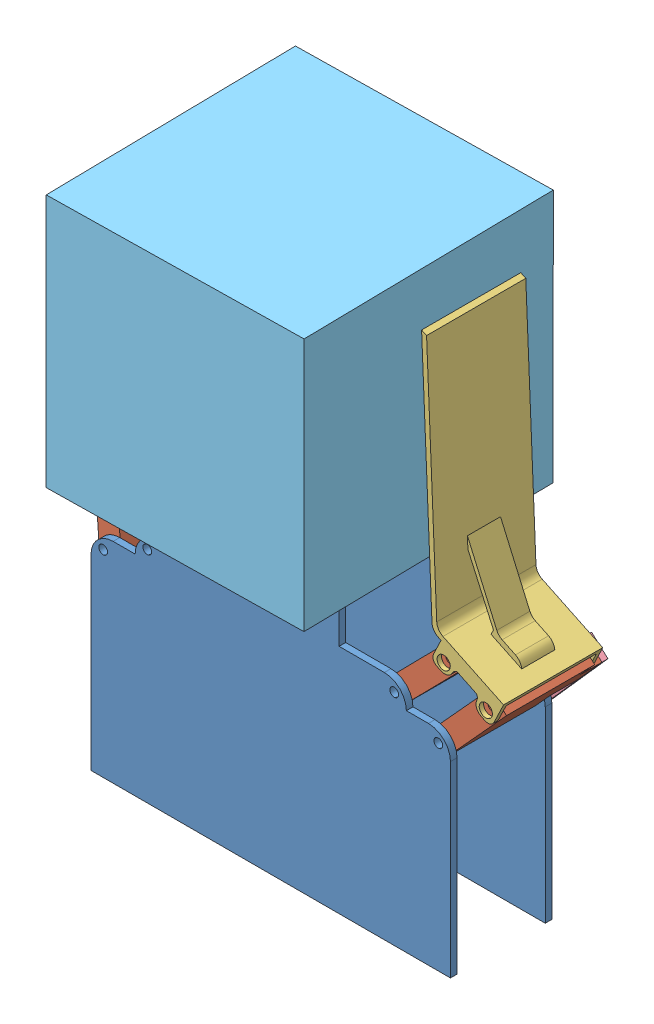
SolidWorks assembly Pince, configuration Défaut. Lengths in mm.
Overall size (282.24 266.51 119.61).
11 component instances, 5 part files, 30 mates.
Components (placement in the parent):
- Piece Rigide maintient-1: Piece Rigide maintient [Défaut] at (-30.132 6.8807 161.5) size (163 143.06 3)
- Bloc mobile-1: Bloc mobile [Défaut] at (-78.272 21.0357 180.8953) x (-0.067561 0.997715 0) z (-0.997715 -0.067561 0) size (40 53 10)
- Bloc mobile-2: Bloc mobile [Défaut] at (-58.671 31.2736 180.8953) x (-0.108315 0.994117 0) z (-0.994117 -0.108315 0) size (40 53 10)
- Bloc mobile-3: Bloc mobile [Défaut] at (59.4896 24.5358 180.8953) x (0.701032 0.713129 0) z (-0.713129 0.701032 0) size (40 53 10)
- Bloc mobile-4: Bloc mobile [Défaut] at (79.3598 14.9216 180.8953) x (0.672919 0.739716 0) z (-0.739716 0.672919 0) size (40 53 10)
- Pièce reliant bloc mobile à pince-1: Pièce reliant bloc mobile à pince [Défaut] at (98.9509 41.1666 185) x (-0.43213 -0.901811 0) z (0 0 1) size (113 89.13 45)
- Pièce reliant bloc mobile à pince-2: Pièce reliant bloc mobile à pince [Défaut] at (-93.0895 49.0766 185) x (0.469909 -0.882715 0) z (0 0 -1) size (113 89.13 45)
- Tige-ax12-1: Tige-ax12 [Défaut] at (-84.7421 -32.1295 144.1112) x (-0.066814 0.986677 0.14834) z (-0.010022 0.148002 -0.988936) size (91.32 31.32 2.5)
- Tige-ax12-2: Tige-ax12 [Défaut] at (44.2318 -23.6934 141.6438) x (0.665474 0.731532 0.14834) z (-0.099821 -0.10973 0.988936) size (91.32 31.32 2.5)
- 4 Cube - Taille totale de 115,115,115mm-2: 4 Cube - Taille totale de 115,115,115mm [Défaut] at (7.2519 73.3451 193.5396) x (0.999854 -0.0006 -0.017076) z (0.0006 1 0) size (115 115 115)
- Piece Rigide maintient-2: Piece Rigide maintient [Défaut] at (-30.132 6.8807 204.5) size (163 143.06 3)
Mates (geometry in assembly coordinates):
- Coaxiale1: concentric anti-aligned: cylinder of Piece Rigide maintient-1 through (-82.6291 11.3715 154.5) axis (0 0 1) radius 2; cylinder of Bloc mobile-1 through (-82.6291 11.3715 214.5) axis (0 0 -1) radius 2
- Coïncidente1: coincident anti-aligned: plane of Piece Rigide maintient-1 through (64.8709 6.8715 164.5) normal (0 0 1); plane of Bloc mobile-1 through (-87.3474 7.0429 164.5) normal (0 0 -1)
- Coaxiale2: concentric anti-aligned: cylinder of Piece Rigide maintient-1 through (-62.6291 21.4394 154.5) axis (0 0 1) radius 2; cylinder of Bloc mobile-2 through (-62.6291 21.4394 214.5) axis (0 0 -1) radius 2
- Coïncidente2: coincident anti-aligned: plane of Piece Rigide maintient-1 through (64.8709 6.8715 164.5) normal (0 0 1); plane of Bloc mobile-2 through (-67.1664 16.9213 164.5) normal (0 0 -1)
- Coaxiale3: concentric anti-aligned: cylinder of Piece Rigide maintient-1 through (49.3709 21.3748 154.5) axis (0 0 1) radius 2; cylinder of Bloc mobile-3 through (49.3709 21.3748 214.5) axis (0 0 -1) radius 2
- Coaxiale4: concentric anti-aligned: cylinder of Piece Rigide maintient-1 through (69.3709 11.3715 154.5) axis (0 0 1) radius 2; cylinder of Bloc mobile-4 through (69.3709 11.3715 214.5) axis (0 0 -1) radius 2
- Coïncidente3: coincident anti-aligned: plane of Piece Rigide maintient-1 through (64.8709 6.8715 164.5) normal (0 0 1); plane of Bloc mobile-3 through (43.0012 22.0275 164.5) normal (0 0 -1)
- Coïncidente4: coincident anti-aligned: plane of Piece Rigide maintient-1 through (64.8709 6.8715 164.5) normal (0 0 1); plane of Bloc mobile-4 through (62.9807 11.7773 164.5) normal (0 0 -1)
- Coaxiale5: concentric anti-aligned: cylinder of Bloc mobile-1 through (-84.791 43.2984 214.5) axis (0 0 -1) radius 2; cylinder of Pièce reliant bloc mobile à pince-2 through (-84.791 43.2984 162.5) axis (0 0 1) radius 3
- Coaxiale6: concentric anti-aligned: cylinder of Bloc mobile-2 through (-66.0951 53.2511 214.5) axis (0 0 -1) radius 2; cylinder of Pièce reliant bloc mobile à pince-2 through (-66.0951 53.2511 162.5) axis (0 0 1) radius 3
- Coïncidente5: coincident anti-aligned: plane of Bloc mobile-2 through (-70.4158 46.7448 164.5) normal (0 0 -1); plane of Pièce reliant bloc mobile à pince-2 through (-85.7423 41.6591 164.5) normal (0 0 1)
- Coaxiale7: concentric anti-aligned: cylinder of Bloc mobile-4 through (90.9043 35.0425 214.5) axis (0 0 -1) radius 2; cylinder of Pièce reliant bloc mobile à pince-1 through (90.9043 35.0425 162.5) axis (0 0 1) radius 3
- Coaxiale8: concentric anti-aligned: cylinder of Bloc mobile-3 through (71.804 44.195 214.5) axis (0 0 -1) radius 2; cylinder of Pièce reliant bloc mobile à pince-1 through (71.804 44.195 162.5) axis (0 0 1) radius 3
- Coïncidente6: coincident anti-aligned: plane of Bloc mobile-3 through (64.0321 43.4214 164.5) normal (0 0 -1); plane of Pièce reliant bloc mobile à pince-1 through (91.9241 33.4449 164.5) normal (0 0 1)
- Coïncidente7: coincident anti-aligned: plane of Bloc mobile-4 through (69.7099 19.1744 151.5) normal (0.099821 0.10973 -0.988936); plane of Tige-ax12-2 through (28.2087 -9.6186 144.1162) normal (-0.099821 -0.10973 0.988936)
- Coïncidente8: coincident aligned: line of Bloc mobile-4 through (83.1682 33.9688 154.5) axis (-0.665474 -0.731532 -0.14834); line of Tige-ax12-2 through (83.1682 33.9688 154.5) axis (-0.665474 -0.731532 -0.14834)
- Coïncidente9: coincident anti-aligned: line of Bloc mobile-4 through (83.1682 33.9688 154.5) axis (0.739716 -0.672919 0); line of Tige-ax12-2 through (90.5654 27.2396 154.5) axis (-0.739716 0.672919 0)
- Coaxiale9: concentric anti-aligned: cylinder of Bloc mobile-1 through (-83.2151 19.328 161.9086) axis (-0.010022 0.148002 -0.988936) radius 1.5; cylinder of Tige-ax12-1 through (-83.3404 21.178 149.5469) axis (0.010022 -0.148002 0.988936) radius 1.5
- Parallèle8: parallel anti-aligned: cylinder of Bloc mobile-1 through (-84.0987 32.3756 163.8702) axis (-0.010022 0.148002 -0.988936) radius 1.5; cylinder of Tige-ax12-1 through (-84.2237 34.2219 151.5079) axis (0.010022 -0.148002 0.988936) radius 1.5
- Parallèle11: parallel aligned: plane of Piece Rigide maintient-1 through (-58.1272 26.9394 164.5) normal (0.0006 1 0); plane of 4 Cube - Taille totale de 115,115,115mm-2 through (7.321 188.3451 193.5396) normal (0.0006 1 0)
- Distance3: distance = 60 mm: point of Piece Rigide maintient-1; point of 4 Cube - Taille totale de 115,115,115mm-2
- Distance4: distance = 60 mm: point of 4 Cube - Taille totale de 115,115,115mm-2; point of Piece Rigide maintient-1
- Coaxiale10: concentric anti-aligned: cylinder of Bloc mobile-3 through (49.3709 21.3748 214.5) axis (0 0 -1) radius 2; cylinder of Piece Rigide maintient-2 through (49.3709 21.3748 197.5) axis (0 0 1) radius 2
- Coaxiale11: concentric anti-aligned: cylinder of Bloc mobile-4 through (69.3709 11.3715 214.5) axis (0 0 -1) radius 2; cylinder of Piece Rigide maintient-2 through (69.3709 11.3715 197.5) axis (0 0 1) radius 2
- Coïncidente16: coincident anti-aligned: plane of Bloc mobile-3 through (43.0012 22.0275 204.5) normal (0 0 1); plane of Piece Rigide maintient-2 through (64.8709 6.8715 204.5) normal (0 0 -1)
- Coaxiale12: concentric anti-aligned: cylinder of Bloc mobile-1 through (-82.6291 11.3715 214.5) axis (0 0 -1) radius 2; cylinder of Piece Rigide maintient-2 through (-82.6291 11.3715 197.5) axis (0 0 1) radius 2
- Coaxiale13: concentric anti-aligned: cylinder of Bloc mobile-2 through (-62.6291 21.4394 214.5) axis (0 0 -1) radius 2; cylinder of Piece Rigide maintient-2 through (-62.6291 21.4394 197.5) axis (0 0 1) radius 2
- Coaxiale16: concentric anti-aligned: cylinder of Bloc mobile-1 through (-83.2151 19.328 161.9086) axis (-0.010022 0.148002 -0.988936) radius 1.5; cylinder of Tige-ax12-1 through (-83.3404 21.178 149.5469) axis (0.010022 -0.148002 0.988936) radius 1.5
- Coïncidente17: coincident anti-aligned: plane of Bloc mobile-1 through (-88.023 17.02 151.5) normal (-0.010022 0.148002 -0.988936); plane of Tige-ax12-1 through (-63.4671 -30.6889 144.1112) normal (0.010022 -0.148002 0.988936)
- Parallèle15: parallel aligned: line of Bloc mobile-1 through (-89.3742 36.9743 154.5) axis (0.997715 0.067561 0); line of Tige-ax12-1 through (-89.4191 36.9378 154.495) axis (0.997715 0.067561 0)
